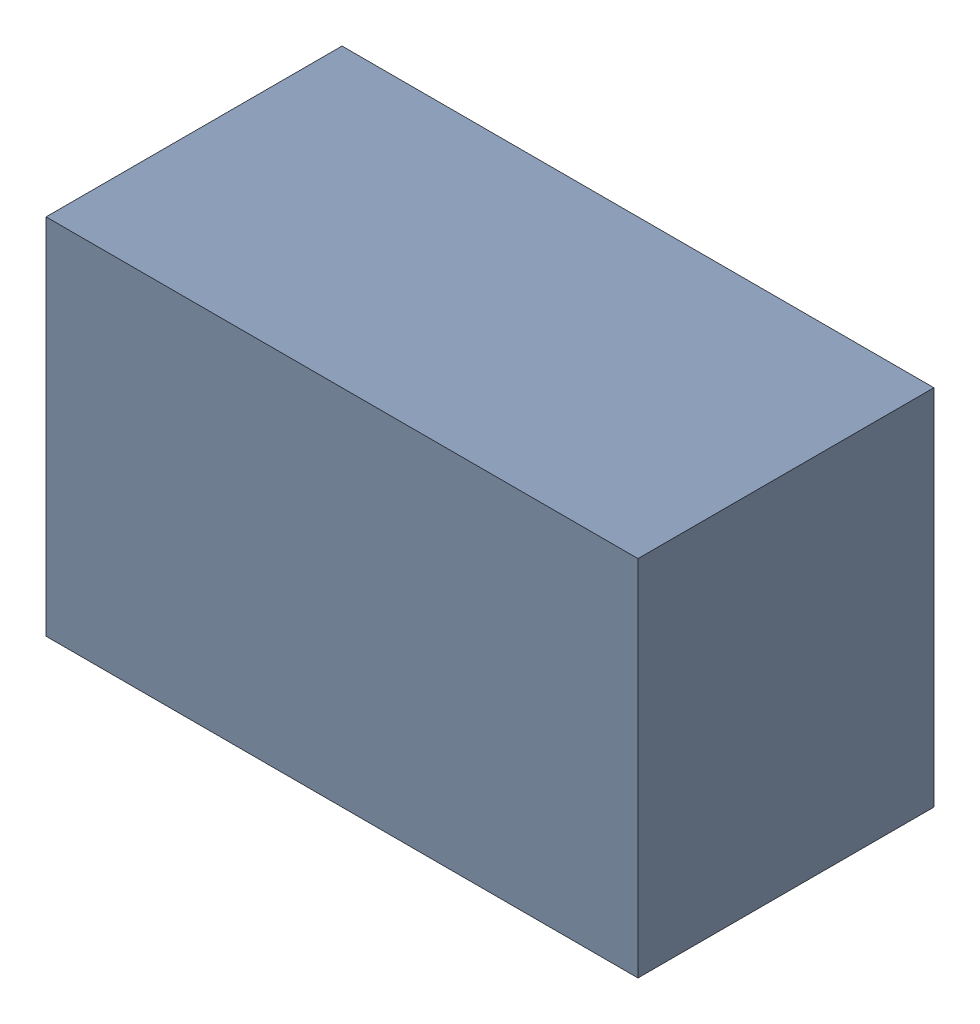
SolidWorks assembly D2, configuration ﾃﾞﾌｫﾙﾄ. Lengths in mm.
Overall size (2.2 1.35 1.1).
2 component instances, 1 part files, 0 mates.
Components (placement in the parent):
- 689260288-1: 689260288 [ﾃﾞﾌｫﾙﾄ] at (16.75 65.25 0) size (2.2 1.35 1.1)
  - Extruded_22-1: Extruded_22 [ﾃﾞﾌｫﾙﾄ] at origin size (2.2 1.35 1.1)
